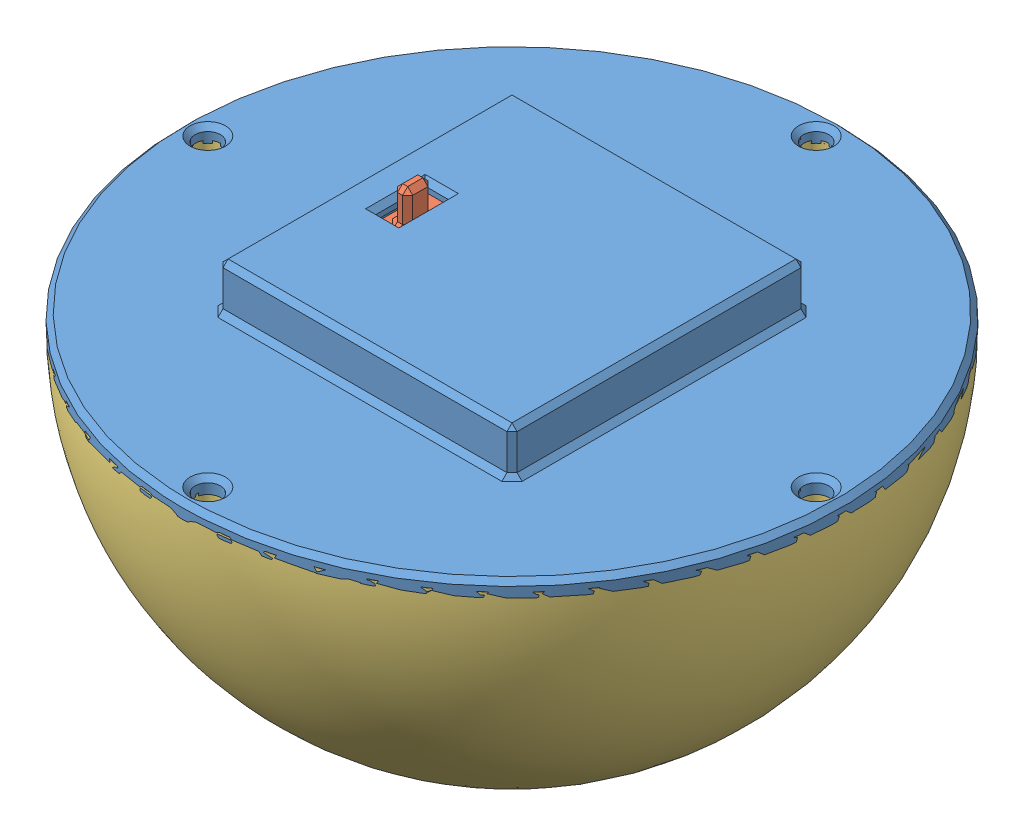
SolidWorks assembly full_assembly, configuration Default. Lengths in mm.
Overall size (130 80.18 130).
3 component instances, 3 part files, 2 mates.
Components (placement in the parent):
- lid-1: lid [Default] at (18.2739 62.1694 126.8927) size (130 12 130)
- on_off_switch-1: on_off_switch [Default] at (19.8 67 110) size (6 12 15)
- lower_part-1: lower_part [Default] at (18.2739 62.1694 126.8927) size (130 74 130)
Mates (geometry in assembly coordinates):
- Parallel8: parallel aligned: plane of lid-1 through (18.2739 74.8194 126.8927) normal (0 1 0); plane of on_off_switch-1 through (19.8 72 110) normal (0 1 0)
- Coincident11: coincident aligned: circle of lid-1; circle of lower_part-1
